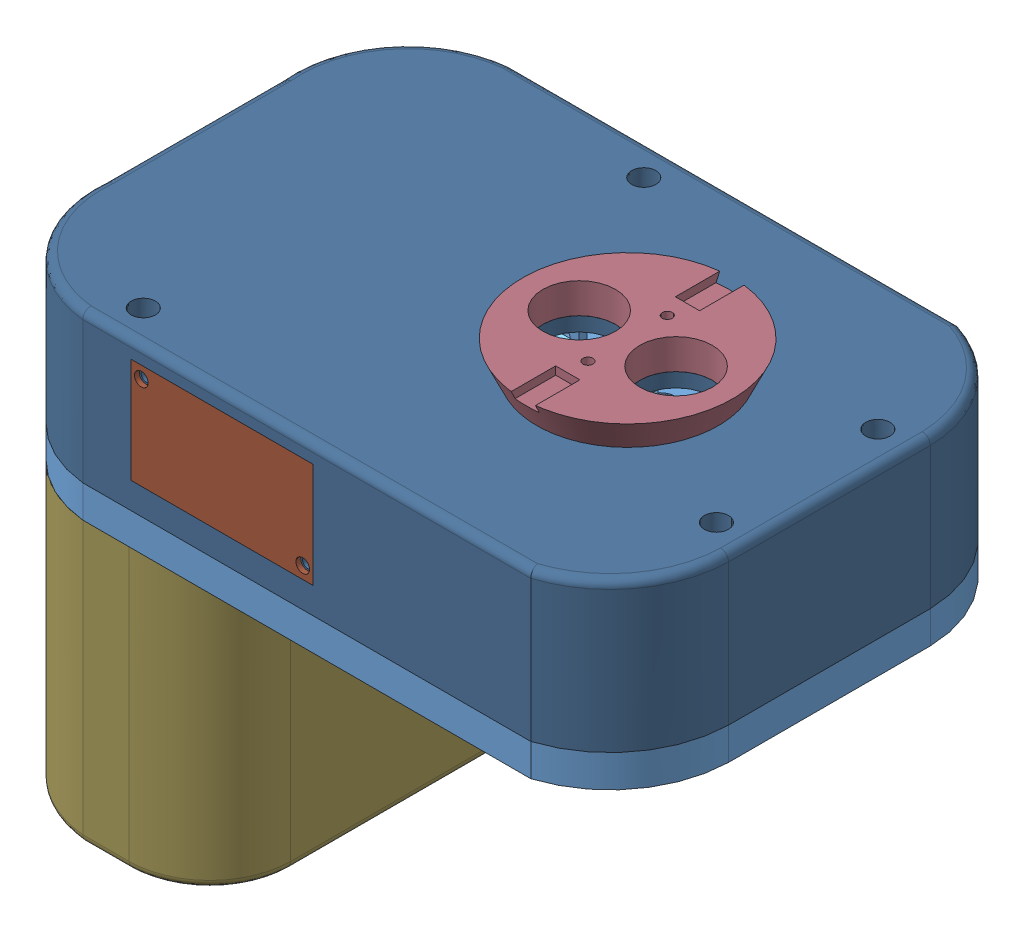
SolidWorks assembly 4th generation HUD new, configuration Default. Lengths in mm.
Overall size (167.5 123.01 106).
14 component instances, 13 part files, 35 mates.
Components (placement in the parent):
- 4th generation Box-1: 4th generation Box [Default] at (41.3448 33.67 140.6977) size (167.5 91 106)
- mount for OLED 3-1: mount for OLED 3 [Default] at (-4.6652 100.67 140.7477) x (0 1 0) z (0 0 -1) size (40 7 33.5)
- lens mount 1-1: lens mount 1 [Default] at (72.3348 103.92 140.7477) x (0 0 1) z (0 -1 0) size (45.5 5 35.5)
- BS mount-1: BS mount [Default] at (119.1648 103.92 140.7477) x (0 0 1) z (0 1 0) size (51.5 7.68 35.5)
- BS model-1: BS model [Default] at (105.4988 104.192 129.0977) x (1 0 0) z (0 -1 0) size (25.4 25.4 25.4)
- BS model-2: BS model [Default] at (78.0988 104.192 129.0977) x (1 0 0) z (0 -1 0) size (25.4 25.4 25.4)
- lens model-1: lens model [Default] at (61.8448 103.92 140.7477) x (0 1 0) z (0 0 1) size (35.8 57.81 35.8)
- MOUNT FOR BS-1: MOUNT FOR BS [Default] at (57.9787 90.1756 159.4977) x (-1 0 0) z (0 -1 0) size (63 2 33.5)
- BS back board 1-1: BS back board 1 [Default] at (78.0988 104.192 154.4977) x (1 0 0) z (0 -1 0) size (25.4 3 25.4)
- BS back board 2-1: BS back board 2 [Default] at (105.4988 104.192 154.4977) x (1 0 0) z (0 -1 0) size (25.4 3 25.4)
- 4th generation Box Cover-1: 4th generation Box Cover [Default] at (41.3421 127.17 140.6977) x (1 0 0) z (0 0 -1) size (157.59 37 106)
- lens focus window-1: lens focus window [Default] at (45.0646 98.0287 192.4977) x (-1 0 0) z (0 1 0) size (45 1.2 26)
- 4th generation Box top cover-1: 4th generation Box top cover [Default] at (41.3421 12.67 140.6977) size (57.1 70.51 106)
- dovetail connector-1: dovetail connector [Default] at (146.3421 127.17 134.6977) x (-1 0 0) z (0 0 1) size (52 7.5 51.65)
Mates (geometry in assembly coordinates):
- Coincident4: coincident anti-aligned: plane of 4th generation Box-1 through (41.3448 85.17 140.6977) normal (0 1 0); plane of lens mount 1-1 through (72.3348 85.17 140.7477) normal (0 -1 0)
- Concentric4: concentric aligned: circle of 4th generation Box-1; circle of lens mount 1-1
- Concentric5: concentric aligned: circle of 4th generation Box-1; circle of lens mount 1-1
- Concentric6: concentric anti-aligned: circle of mount for OLED 3-1; circle of lens mount 1-1
- Concentric7: concentric anti-aligned: circle of mount for OLED 3-1; circle of lens mount 1-1
- Coincident5: coincident anti-aligned: plane of mount for OLED 3-1 through (2.3348 100.67 140.7477) normal (1 0 0); plane of lens mount 1-1 through (2.3348 103.92 140.7477) normal (-1 0 0)
- Concentric8: concentric aligned: circle of 4th generation Box-1; circle of BS mount-1
- Concentric9: concentric aligned: circle of 4th generation Box-1; circle of BS mount-1
- Coincident6: coincident anti-aligned: plane of 4th generation Box-1 through (41.3448 85.17 140.6977) normal (0 1 0); plane of BS mount-1 through (119.1648 85.17 140.7477) normal (0 -1 0)
- Coincident7: coincident anti-aligned: plane of BS mount-1 through (189.1648 87.17 157.4977) normal (0 0 1); plane of MOUNT FOR BS-1 through (57.9787 90.1756 157.4977) normal (0 0 -1)
- Concentric10: concentric anti-aligned: circle of BS mount-1; circle of MOUNT FOR BS-1
- Concentric11: concentric anti-aligned: circle of BS mount-1; circle of MOUNT FOR BS-1
- Coincident8: coincident anti-aligned: plane of MOUNT FOR BS-1 through (57.9787 90.1756 157.4977) normal (0 0 -1); plane of BS back board 2-1 through (105.4988 104.192 157.4977) normal (0 0 1)
- Concentric12: concentric anti-aligned: circle of MOUNT FOR BS-1; circle of BS back board 2-1
- Coincident9: coincident anti-aligned: plane of MOUNT FOR BS-1 through (57.9787 90.1756 157.4977) normal (0 0 -1); plane of BS back board 1-1 through (78.0988 104.192 157.4977) normal (0 0 1)
- Concentric13: concentric anti-aligned: circle of MOUNT FOR BS-1; circle of BS back board 1-1
- Coincident10: coincident anti-aligned: plane of BS model-1 through (105.4988 104.192 154.4977) normal (0 0 1); plane of BS back board 2-1 through (105.4988 104.192 154.4977) normal (0 0 -1)
- Coincident11: coincident aligned: line of BS model-1 through (118.1988 116.892 154.4977) axis (-1 0 0); line of BS back board 2-1 through (118.1988 116.892 154.4977) axis (-1 0 0)
- Coincident12: coincident aligned: line of BS model-1 through (118.1988 91.492 154.4977) axis (0 1 0); line of BS back board 2-1 through (118.1988 91.492 154.4977) axis (0 1 0)
- Coincident13: coincident anti-aligned: plane of BS model-2 through (78.0988 104.192 154.4977) normal (0 0 1); plane of BS back board 1-1 through (78.0988 104.192 154.4977) normal (0 0 -1)
- Coincident14: coincident aligned: line of BS model-2 through (90.7988 91.492 154.4977) axis (0 1 0); line of BS back board 1-1 through (90.7988 91.492 154.4977) axis (0 1 0)
- Coincident15: coincident aligned: line of BS model-2 through (65.3988 91.492 154.4977) axis (1 0 0); line of BS back board 1-1 through (65.3988 91.492 154.4977) axis (1 0 0)
- Concentric14: concentric anti-aligned: circle of lens mount 1-1; circle of lens model-1
- Coincident16: coincident anti-aligned: plane of lens mount 1-1 through (7.3348 120.67 117.9977) normal (1 0 0); plane of lens model-1 through (7.3348 103.92 140.7477) normal (-1 0 0)
- Coincident20: coincident: line of 4th generation Box-1 through (12.8448 90.17 193.6977) axis (1 0 0); line of 4th generation Box Cover-1 through (123.8421 90.17 193.6977) axis (-1 0 0)
- Coincident21: coincident: line of 4th generation Box-1 through (-12.6079 90.17 118.6977) axis (0 0 1); line of 4th generation Box Cover-1 through (-12.6079 90.17 162.6977) axis (0 0 -1)
- Concentric15: concentric: circle of 4th generation Box Cover-1; circle of lens focus window-1
- Coincident23: coincident: plane of 4th generation Box Cover-1 through (41.3421 127.17 192.4977) normal (0 0 1); plane of lens focus window-1 through (45.0646 98.0287 192.4977) normal (0 0 -1)
- Concentric17: concentric aligned: circle of 4th generation Box Cover-1; circle of lens focus window-1
- Coincident24: coincident: plane of 4th generation Box-1 through (41.3448 82.17 140.6977) normal (0 -1 0); plane of 4th generation Box top cover-1 through (114.8421 82.17 165.0727) normal (0 1 0)
- Coincident25: coincident: line of 4th generation Box-1 through (-12.6079 82.17 162.6977) axis (0 0 -1); line of 4th generation Box top cover-1 through (-12.6079 82.17 118.6977) axis (0 0 1)
- Coincident26: coincident anti-aligned: line of 4th generation Box-1 through (12.8448 82.17 87.6977) axis (1 0 0); line of 4th generation Box top cover-1 through (24.3521 82.17 87.6977) axis (-1 0 0)
- Coincident27: coincident: plane of 4th generation Box Cover-1 through (41.3421 127.17 140.6977) normal (0 1 0); plane of dovetail connector-1 through (93.8421 127.17 139.6977) normal (0 -1 0)
- Concentric18: concentric: circle of 4th generation Box Cover-1; circle of dovetail connector-1
- Concentric19: concentric aligned: circle of 4th generation Box Cover-1; circle of dovetail connector-1
